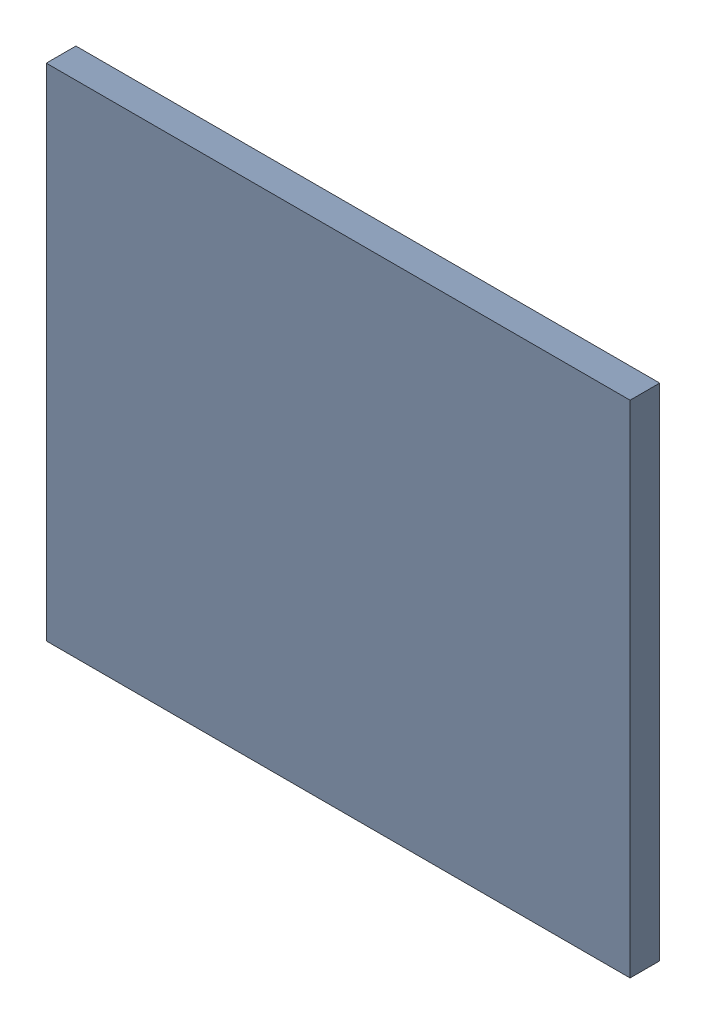
SolidWorks assembly Pad R4-1(28.05mm,41.5mm) on Top Layer, configuration Predeterminado. Lengths in mm.
Overall size (0.7 0.6 0.04).
2 component instances, 1 part files, 0 mates.
Components (placement in the parent):
- Pad R4-1(28.05mm,41.5mm) on Top Layer-1-1: Pad R4-1(28.05mm,41.5mm) on Top Layer-1 [Predeterminado] at (-68.317 -44.187 -0.0457) size (0.7 0.6 0.04)
  - Pad R4-1(28.05mm,41.5mm) on Top Layer-Part-1-1: Pad R4-1(28.05mm,41.5mm) on Top Layer-Part-1 [Predeterminado] at origin size (0.7 0.6 0.04)
